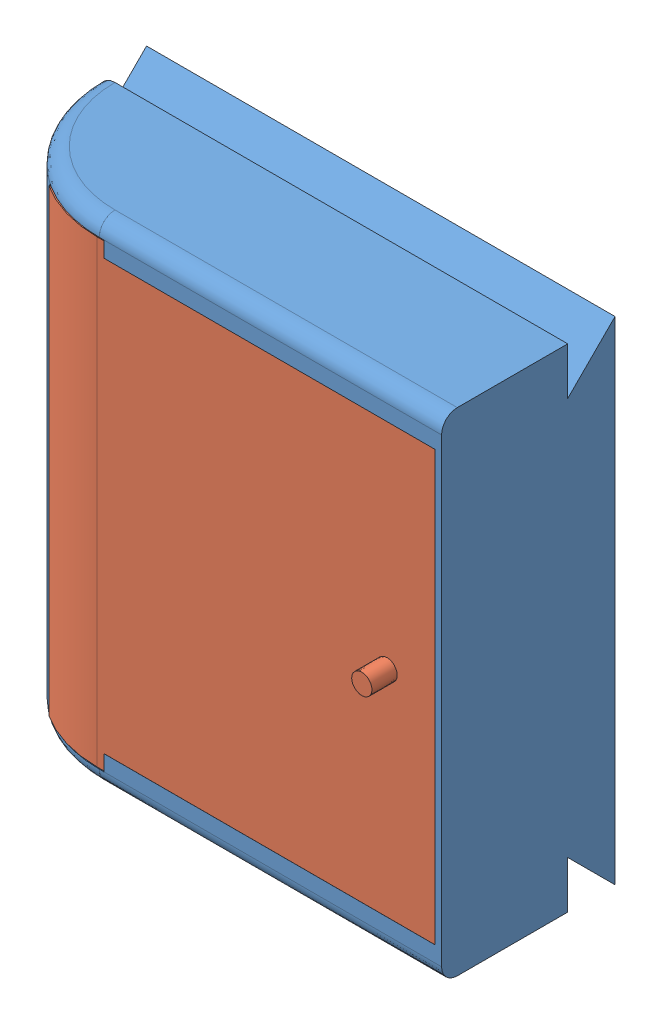
SolidWorks assembly Assem3, configuration Default. Lengths in mm.
Overall size (148.5 156 62.98).
2 component instances, 2 part files, 2 mates.
Components (placement in the parent):
- Compartment - No Tolerance-1: Compartment - No Tolerance [Default] at origin size (148.5 156 55)
- compartment door - No tolerance-2: compartment door - No tolerance [Default] at (-59.6798 0 -0.0161) x (0 0 1) z (-1 0 0) size (14.5 145.5 129)
Mates (geometry in assembly coordinates):
- Coincident2: coincident anti-aligned: plane of Compartment-1 through (-65.3727 -7.95 37.6679) normal (0 -0.702701 0.711485); plane of compartment door - No tolerance-2 through (45.3202 -7.95 37.6679) normal (0 0.702701 -0.711485)
- Coincident3: coincident anti-aligned: plane of Compartment-1 through (-65.3727 -152.05 37.6679) normal (0 0.702701 0.711485); plane of compartment door - No tolerance-2 through (45.3202 -148 33.6679) normal (0 -0.702701 -0.711485)
